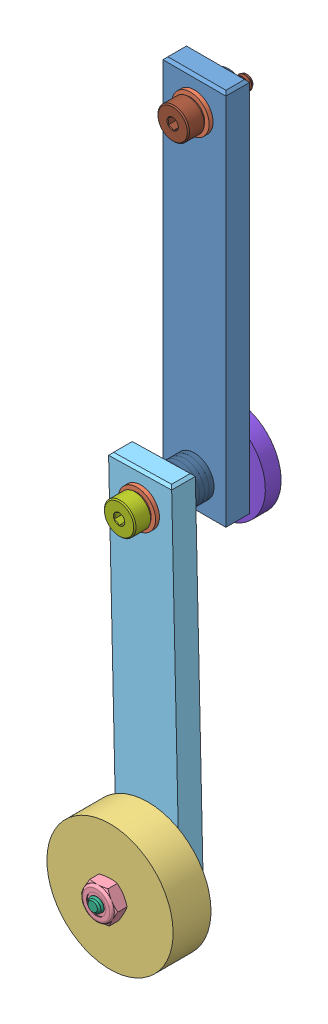
SolidWorks assembly pendulum, configuration Default. Lengths in mm.
Overall size (33.83 149.65 33.45).
25 component instances, 11 part files, 34 mates.
Components (placement in the parent):
- top_link_assy-1: top_link_assy [Default] at origin size (12.7 76.2 6.34) (flexible)
  - top_link-1: top_link [Default] at (0 -6.35 4.7625) x (0 1 0) z (-1 0 0) size (76.2 4.76 12.7)
  - FR144-ZZ-3: FR144-ZZ [Default] at (0 -6.35 2.7464) x (-0.97513 -0.221634 0) z (0 0 1) size (7.52 7.52 2.8)
  - FR144-ZZ-4: FR144-ZZ [Default] at (0 -6.35 2.0161) x (0.985651 0.168793 0) z (0 0 -1) size (7.52 7.52 2.8)
- bottom_link_assy-1: bottom_link_assy [Default] at (-0.1423 -63.5016 10.7823) x (0.999749 0.022416 0) z (0 0 1) size (31.92 85.81 16.92)
  - Mass_blank-1: Mass_blank [Default] at (0 -69.85 4.7625) x (0.9527 0.303914 0) z (0 0 1) size (25.4 25.4 7.62)
  - 4_40_THIN_LOCKNUT_90633A005-1: 4_40_THIN_LOCKNUT_90633A005 [90633A005] at (0 -69.85 12.3825) x (0.853828 0.520556 0) z (0.520556 -0.853828 0) size (6.35 2.86 7.33)
  - bottom_link-1: bottom_link [Default] at (0 -6.35 4.7625) x (0 1 0) z (-1 0 0) size (76.2 4.76 12.7)
  - 4_40-625-countersunk-stainless-92210a112-1: 4_40-625-countersunk-stainless-92210a112 [92210A112] at (0 -69.85 0) x (-0.923728 -0.383049 0) z (0 0 -1) size (6.48 6.48 16.22)
  - FR144-ZZ-1: FR144-ZZ [Default] at (0 -6.35 2.7464) size (7.52 7.52 2.8)
  - FR144-ZZ-2: FR144-ZZ [Default] at (0 -6.35 2.0161) x (-0.923728 -0.383049 0) z (0 0 -1) size (7.52 7.52 2.8)
- 4_40-3-4-94035A138-1: 4_40-3-4-94035A138 [94035A138] at (0 -69.85 19.9136) x (-0.54251 -0.840049 0) z (0 0 1) size (6.35 6.35 26.56)
- RC22-1: RC22 [Default] at (0 -69.85 -3.175) x (0.220805 0.975318 0) z (0.975318 -0.220805 0) size (19.05 3.17 19.05)
- bearing_spacer_ 99040A316-1: bearing_spacer_ 99040A316 [Default] at (0 -69.85 16.7386) x (0.923728 0.383049 0) z (0 0 -1) size (4.76 4.76 0.41)
- 4_40_THIN_LOCKNUT_90633A005-1: 4_40_THIN_LOCKNUT_90633A005 [90633A005] at (0 -69.85 -3.175) x (0.830959 0.556334 0) z (-0.556334 0.830959 0) size (6.35 2.86 7.33)
- 4_40-Washer_AL_93286A005-8: 4_40-Washer_AL_93286A005 [93286A005] at (0 -69.85 5.7277) x (0 0 -1) z (1 0 0) size (0.97 7.92 7.92)
- bearing_spacer_ 99040A316-2: bearing_spacer_ 99040A316 [Default] at (0 -69.85 9.9949) x (0.923728 0.383049 0) z (0 0 -1) size (4.76 4.76 0.41)
- 4_40-Washer_AL_93286A005-7: 4_40-Washer_AL_93286A005 [93286A005] at (0 -69.85 6.6929) x (0 0 -1) z (0.432498 -0.901635 0) size (0.97 7.92 7.92)
- bearing_spacer_ 99040A316-3: bearing_spacer_ 99040A316 [Default] at (0 -6.35 5.5499) x (0.019518 -0.99981 0) z (0 0 1) size (4.76 4.76 0.41)
- bearing_spacer_ 99040A316-4: bearing_spacer_ 99040A316 [Default] at (0 -6.35 -0.7874) x (-0.923728 -0.383049 0) z (0 0 -1) size (4.76 4.76 0.41)
- 4_40-Washer_AL_93286A005-6: 4_40-Washer_AL_93286A005 [93286A005] at (0 -6.35 -1.1938) x (0 0 -1) z (0.512849 -0.858479 0) size (0.97 7.92 7.92)
- 4_40-5-16_94035A517_new-1: 4_40-5-16_94035A517_new [94035A517] at (0 -6.35 9.1313) x (0.996772 0.080284 0) z (0 0 1) size (6.35 6.35 15.45)
- 4_40-Washer_AL_93286A005-9: 4_40-Washer_AL_93286A005 [93286A005] at (0 -69.85 7.6581) x (0 0 -1) z (1 0 0) size (0.97 7.92 7.92)
- 4_40-Washer_AL_93286A005-5: 4_40-Washer_AL_93286A005 [93286A005] at (0 -69.85 8.6233) x (0 0 -1) z (0.988714 -0.149814 0) size (0.97 7.92 7.92)
- 4_40-Washer_AL_93286A005-10: 4_40-Washer_AL_93286A005 [93286A005] at (0 -69.85 9.5885) x (0 0 -1) z (0.999961 0.008844 0) size (0.97 7.92 7.92)
Mates (geometry in assembly coordinates):
- Coincident33: coincident anti-aligned: plane of top_link_assy-1/top_link-1 through (0 -6.35 0) normal (0 0 -1); plane of assembly through (0 0 0) normal (0 0 1)
- Coincident34: coincident aligned: plane of top_link_assy-1/top_link-1 through (0 0 0) normal (0 1 0); plane of assembly through (0 0 0) normal (0 1 0)
- Symmetric2: symmetric aligned: plane of top_link_assy-1/top_link-1 through (-6.35 -6.35 0) normal (-1 0 0); plane of top_link_assy-1/top_link-1 through (6.35 -6.35 0) normal (1 0 0); plane of assembly through (0 0 0) normal (1 0 0)
- Concentric31: concentric anti-aligned: cylinder of 4_40-Washer_AL_93286A005-7 through (0 -69.85 5.7277) axis (0 0 1) radius 1.5875; cylinder of top_link_assy-1/top_link-1 through (0 -69.85 0) axis (0 0 -1) radius 1.632
- Concentric17: concentric aligned: cylinder of RC22-1 through (0 -69.85 0) axis (0 0 -1) radius 1.5875; cylinder of 4_40-3-4-94035A138-1 through (0 -69.85 -6.2801) axis (0 0 -1) radius 1.5875
- Coincident22: coincident anti-aligned: plane of top_link_assy-1/top_link-1 through (0 -6.35 0) normal (0 0 -1); plane of RC22-1 through (0 -69.85 0) normal (0 0 1)
- Coincident23: coincident anti-aligned: plane of RC22-1 through (0 -69.85 -3.175) normal (0 0 -1); plane of 4_40_THIN_LOCKNUT_90633A005-1 through (0.4211 -76.186 -3.175) normal (0 0 1)
- Concentric18: concentric anti-aligned: cylinder of RC22-1 through (0 -69.85 0) axis (0 0 -1) radius 1.5875; cylinder of 4_40_THIN_LOCKNUT_90633A005-1 through (0 -69.85 -5.5663) axis (0 0 1) radius 1.1475
- Concentric23: concentric anti-aligned: cylinder of 4_40-3-4-94035A138-1 through (0 -69.85 -6.2801) axis (0 0 -1) radius 1.5875; cylinder of 4_40-Washer_AL_93286A005-8 through (0 -69.85 4.7625) axis (0 0 1) radius 1.5875
- Coincident35: coincident anti-aligned: plane of 4_40-3-4-94035A138-1 through (-2.6672 -68.1275 16.7386) normal (0 0 -1); plane of bearing_spacer_ 99040A316-1 through (0 -69.85 16.7386) normal (0 0 1)
- Coincident36: coincident anti-aligned: plane of top_link_assy-1/top_link-1 through (0 -6.35 4.7625) normal (0 0 1); plane of 4_40-Washer_AL_93286A005-8 through (0 -69.85 4.7625) normal (0 0 -1)
- Concentric37: concentric anti-aligned: cylinder of 4_40-3-4-94035A138-1 through (0 -69.85 -6.2801) axis (0 0 -1) radius 1.5875; cylinder of 4_40-Washer_AL_93286A005-7 through (0 -69.85 5.7277) axis (0 0 1) radius 1.5875
- Coincident47: coincident anti-aligned: plane of 4_40-Washer_AL_93286A005-8 through (0 -69.85 5.7277) normal (0 0 1); plane of 4_40-Washer_AL_93286A005-7 through (0 -69.85 5.7277) normal (0 0 -1)
- Concentric38: concentric anti-aligned: cylinder of bottom_link_assy-1/FR144-ZZ-1 through (0 -69.85 15.5448) axis (0 0 -1) radius 1.5875; cylinder of 4_40-Washer_AL_93286A005-7 through (0 -69.85 5.7277) axis (0 0 1) radius 1.5875
- Coincident49: coincident anti-aligned: plane of bearing_spacer_ 99040A316-2 through (0 -69.85 9.9949) normal (0 0 1); plane of bottom_link_assy-1/FR144-ZZ-2 through (0 -69.85 9.9949) normal (0 0 -1)
- Concentric39: concentric aligned: cylinder of 4_40-3-4-94035A138-1 through (0 -69.85 -6.2801) axis (0 0 -1) radius 1.5875; cylinder of bottom_link_assy-1/FR144-ZZ-1 through (0 -69.85 15.5448) axis (0 0 -1) radius 1.5875
- Coincident50: coincident anti-aligned: plane of bearing_spacer_ 99040A316-1 through (0 -69.85 16.3322) normal (0 0 -1); plane of bottom_link_assy-1/FR144-ZZ-1 through (0 -69.85 16.3322) normal (0 0 1)
- Concentric40: concentric anti-aligned: cylinder of 4_40-3-4-94035A138-1 through (0 -69.85 -6.2801) axis (0 0 -1) radius 1.5875; cylinder of bearing_spacer_ 99040A316-2 through (0 -69.85 9.5885) axis (0 0 1) radius 1.5875
- Concentric41: concentric anti-aligned: cylinder of 4_40-3-4-94035A138-1 through (0 -69.85 -6.2801) axis (0 0 -1) radius 1.5875; cylinder of bearing_spacer_ 99040A316-1 through (0 -69.85 16.3322) axis (0 0 1) radius 1.5875
- Concentric42: concentric aligned: cylinder of top_link_assy-1/FR144-ZZ-3 through (0 -6.35 4.7625) axis (0 0 -1) radius 1.5875; cylinder of bearing_spacer_ 99040A316-3 through (0 -6.35 5.9563) axis (0 0 -1) radius 1.5875
- Coincident51: coincident anti-aligned: plane of top_link_assy-1/FR144-ZZ-3 through (0 -6.35 5.5499) normal (0 0 1); plane of bearing_spacer_ 99040A316-3 through (0 -6.35 5.5499) normal (0 0 -1)
- Coincident53: coincident anti-aligned: plane of top_link_assy-1/FR144-ZZ-4 through (0 -6.35 -0.7874) normal (0 0 -1); plane of bearing_spacer_ 99040A316-4 through (0 -6.35 -0.7874) normal (0 0 1)
- Concentric44: concentric aligned: cylinder of top_link_assy-1/FR144-ZZ-4 through (0 -6.35 0) axis (0 0 1) radius 1.5875; cylinder of bearing_spacer_ 99040A316-4 through (0 -6.35 -1.1938) axis (0 0 1) radius 1.5875
- Concentric45: concentric aligned: cylinder of bearing_spacer_ 99040A316-4 through (0 -6.35 -1.1938) axis (0 0 1) radius 1.5875; cylinder of 4_40-Washer_AL_93286A005-6 through (0 -6.35 -2.159) axis (0 0 1) radius 1.5875
- Coincident54: coincident anti-aligned: plane of bearing_spacer_ 99040A316-4 through (0 -6.35 -1.1938) normal (0 0 -1); plane of 4_40-Washer_AL_93286A005-6 through (0 -6.35 -1.1938) normal (0 0 1)
- Concentric47: concentric aligned: cylinder of bearing_spacer_ 99040A316-3 through (0 -6.35 5.9563) axis (0 0 -1) radius 1.5875; cylinder of 4_40-5-16_94035A517_new-1 through (0 -6.35 -5.95) axis (0 0 -1) radius 1.5875
- Coincident55: coincident anti-aligned: circle of bearing_spacer_ 99040A316-3; plane of 4_40-5-16_94035A517_new-1 through (0.2549 -9.5148 5.9563) normal (0 0 -1)
- Concentric48: concentric aligned: cylinder of 4_40-Washer_AL_93286A005-7 through (0 -69.85 5.7277) axis (0 0 1) radius 1.5875; cylinder of 4_40-Washer_AL_93286A005-9 through (0 -69.85 6.6929) axis (0 0 1) radius 1.5875
- Coincident56: coincident anti-aligned: plane of 4_40-Washer_AL_93286A005-7 through (0 -69.85 6.6929) normal (0 0 1); plane of 4_40-Washer_AL_93286A005-9 through (0 -69.85 6.6929) normal (0 0 -1)
- Concentric49: concentric aligned: cylinder of 4_40-Washer_AL_93286A005-9 through (0 -69.85 6.6929) axis (0 0 1) radius 1.5875; cylinder of 4_40-Washer_AL_93286A005-5 through (0 -69.85 7.6581) axis (0 0 1) radius 1.5875
- Coincident57: coincident anti-aligned: plane of 4_40-Washer_AL_93286A005-9 through (0 -69.85 7.6581) normal (0 0 1); plane of 4_40-Washer_AL_93286A005-5 through (0 -69.85 7.6581) normal (0 0 -1)
- Concentric50: concentric aligned: cylinder of 4_40-Washer_AL_93286A005-9 through (0 -69.85 6.6929) axis (0 0 1) radius 1.5875; cylinder of 4_40-Washer_AL_93286A005-10 through (0 -69.85 8.6233) axis (0 0 1) radius 1.5875
- Coincident58: coincident anti-aligned: plane of 4_40-Washer_AL_93286A005-5 through (0 -69.85 8.6233) normal (0 0 1); plane of 4_40-Washer_AL_93286A005-10 through (0 -69.85 8.6233) normal (0 0 -1)
- Coincident59: coincident anti-aligned: plane of bearing_spacer_ 99040A316-2 through (0 -69.85 9.5885) normal (0 0 -1); plane of 4_40-Washer_AL_93286A005-10 through (0 -69.85 9.5885) normal (0 0 1)
